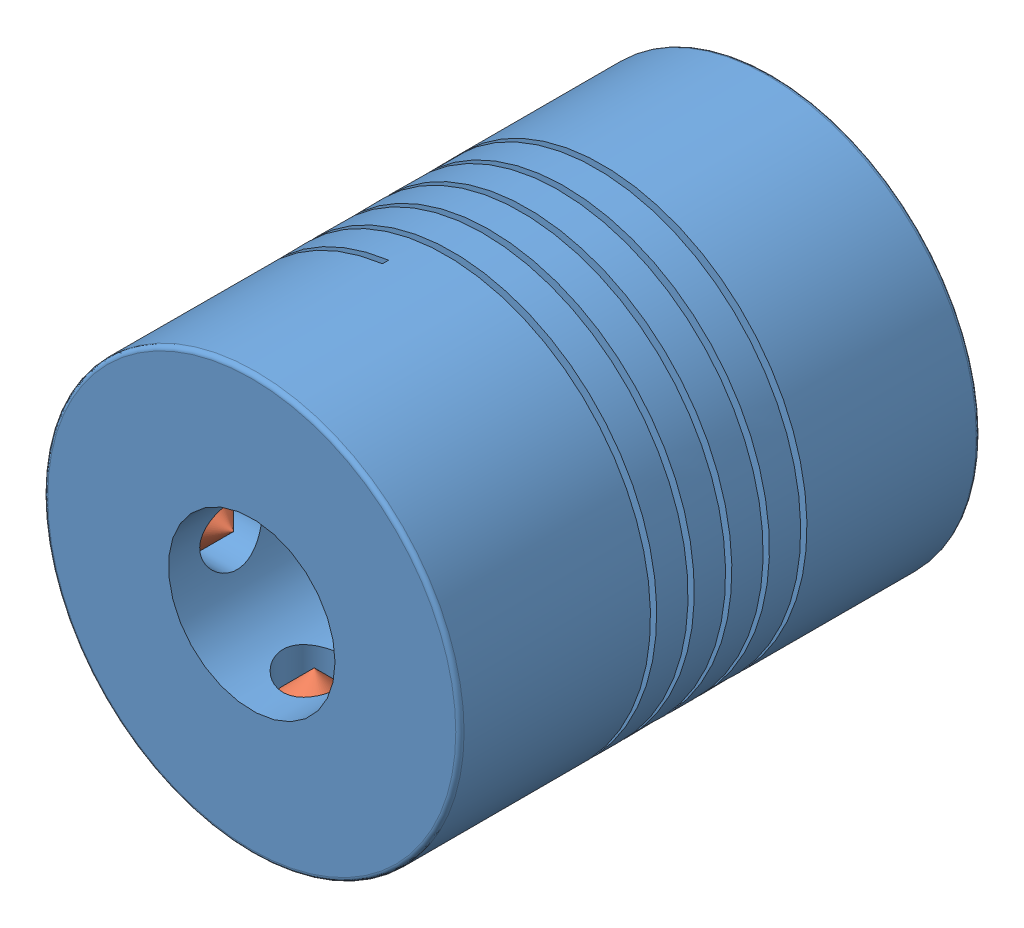
SolidWorks assembly Acople Flexible, configuration Predeterminado. Lengths in mm.
Overall size (20.77 20.77 25).
5 component instances, 2 part files, 4 mates.
Components (placement in the parent):
- Acople FlexibleSLDPRT-1: Acople FlexibleSLDPRT [Predeterminado] at (-1.3837 -0.8648 0) size (20.77 20.77 25)
- socket set screw cone point_am-7: socket set screw cone point_am [B18.3.6M - M3 x 0.5 x 6 Hex Socket Cone Pt. SS --N] at (-11.2647 -0.8648 22) x (1 0 0) z (0 -0.164849 0.986319) size (6 3 3)
- socket set screw cone point_am-8: socket set screw cone point_am [B18.3.6M - M3 x 0.5 x 6 Hex Socket Cone Pt. SS --N] at (-11.1909 -0.8648 3) x (1 0 0) z (0 0.00677 0.999977) size (6 3 3)
- socket set screw cone point_am-9: socket set screw cone point_am [B18.3.6M - M3 x 0.5 x 6 Hex Socket Cone Pt. SS --N] at (-1.3837 -10.7654 3) x (0 1 0) z (-0.345086 0 0.938571) size (6 3 3)
- socket set screw cone point_am-10: socket set screw cone point_am [B18.3.6M - M3 x 0.5 x 6 Hex Socket Cone Pt. SS --N] at (-1.3837 -10.5992 22) x (0 1 0) z (-0.865685 0 0.500588) size (6 3 3)
Mates (geometry in assembly coordinates):
- Concéntrica7: concentric: cylinder of Acople FlexibleSLDPRT-1 through (-161.3837 -0.8648 22) axis (1 0 0) radius 1.5; cylinder of socket set screw cone point_am-7 through (-23.9647 -0.8648 22) axis (-1 0 0) radius 1.5
- Concéntrica8: concentric: cylinder of Acople FlexibleSLDPRT-1 through (-161.3837 -0.8648 3) axis (1 0 0) radius 1.5; cylinder of socket set screw cone point_am-8 through (-23.8909 -0.8648 3) axis (-1 0 0) radius 1.5
- Concéntrica10: concentric: cylinder of Acople FlexibleSLDPRT-1 through (-1.3837 -18.8648 3) axis (0 1 0) radius 1.5; cylinder of socket set screw cone point_am-9 through (-1.3837 -23.4654 3) axis (0 -1 0) radius 1.5
- Concéntrica11: concentric: cylinder of Acople FlexibleSLDPRT-1 through (-1.3837 -18.8648 22) axis (0 1 0) radius 1.5; cylinder of socket set screw cone point_am-10 through (-1.3837 -23.2992 22) axis (0 -1 0) radius 1.5
